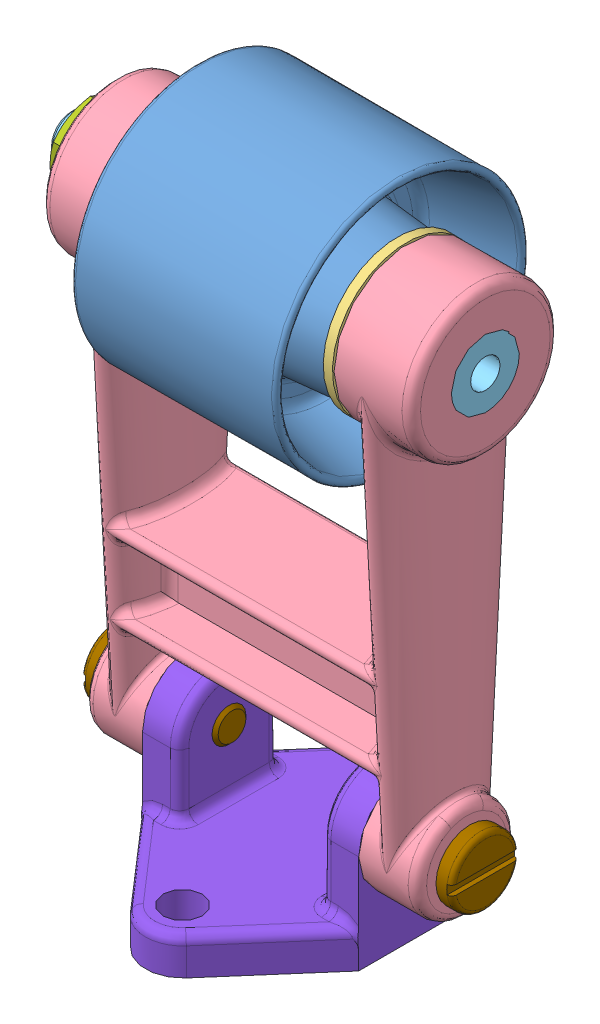
SolidWorks assembly ASSEMBLY v1, configuration Default. Lengths in mm.
Overall size (134.09 213.84 100).
11 component instances, 9 part files, 23 mates.
Components (placement in the parent):
- PULLEY v2-1: PULLEY v2 [Default] at origin size (68.15 83.68 83.68)
- BUSHING v2-1: BUSHING v2 [Default] at origin size (63 26.9 26.9)
- WASHER v1-1: WASHER v1 [Default] at (31.5 0 0) x (0 0.448797 -0.893634) z (-1 0 0) size (48 48 3)
- WASHER v1-2: WASHER v1 [Default] at (-34.5 0 0) x (0 0.448797 -0.893634) z (-1 0 0) size (48 48 3)
- Frame_final-1: Frame_final [Default] at (0 -140 0) size (120 180 51.83)
- SHAFT-1: SHAFT [Default] at (-7 0 0) size (134 22 22)
- WOODRUFF KEY #406-1: WOODRUFF KEY #406 [Default] at (-46 11.1125 0) size (18.79 7.95 3.17)
- HEX NUT V1-2: HEX NUT V1 [Default] at (-69 0 0) x (-1 0 0) z (0 0 1) size (9 27.71 24)
- BRACKET-1: BRACKET [Default] at (0 -172 0) x (0 0 -1) z (1 0 0) size (100 48 70.6)
- PIN v2-1: PIN v2 [Default] at (-60 -140 0) size (38.09 22 22)
- PIN v2-2: PIN v2 [Default] at (60 -140 0) x (-1 0 0) z (0 0 -1) size (38.09 22 22)
Mates (geometry in assembly coordinates):
- Concentric1: concentric aligned: cylinder of PULLEY v2-1 through (-113.6273 0 0) axis (-1 0 0) radius 13.45; cylinder of BUSHING v2-1 through (-66.3727 0 0) axis (-1 0 0) radius 13.45
- Coincident1: coincident aligned: plane of PULLEY v2-1 through (31.5 22 0) normal (1 0 0); plane of BUSHING v2-1 through (31.5 13.45 0) normal (1 0 0)
- Coincident2: coincident aligned: plane of BUSHING v2-1 through (0 0 0) normal (0 0 1); plane of assembly through (0 0 0) normal (0 0 1)
- Concentric4: concentric aligned: cylinder of BUSHING v2-1 through (-66.3727 0 0) axis (-1 0 0) radius 9.6216; cylinder of WASHER v1-1 through (34.501 0 0) axis (-1 0 0) radius 9.5
- Coincident4: coincident anti-aligned: plane of BUSHING v2-1 through (31.5 13.45 0) normal (1 0 0); plane of WASHER v1-1 through (31.5 0 0) normal (-1 0 0)
- Concentric5: concentric anti-aligned: cylinder of BUSHING v2-1 through (-66.3727 0 0) axis (-1 0 0) radius 9.6216; cylinder of Frame_final-1 through (-60.001 0 0) axis (1 0 0) radius 11
- Distance1: distance = 35 mm aligned: plane of Frame_final-1 through (-35 0 0) normal (1 0 0); plane of assembly through (0 0 0) normal (1 0 0)
- Coincident6: coincident aligned: plane of Frame_final-1 through (0 -140 0) normal (0 0 1); plane of assembly through (0 0 0) normal (0 0 1)
- Concentric6: concentric anti-aligned: cylinder of SHAFT-1 through (-46 11.1125 -1.5875) axis (0 0 1) radius 9.525; cylinder of WOODRUFF KEY #406-1 through (-46 11.1125 1.5875) axis (0 0 -1) radius 9.525
- Coincident7: coincident aligned: plane of SHAFT-1 through (-7 0 0) normal (0 0 1); plane of WOODRUFF KEY #406-1 through (-46 11.1125 0) normal (0 0 1)
- Concentric7: concentric anti-aligned: cylinder of Frame_final-1 through (-60.001 0 0) axis (1 0 0) radius 11; cylinder of SHAFT-1 through (-91.9355 0 0) axis (-1 0 0) radius 11
- Coincident8: coincident aligned: plane of Frame_final-1 through (60 0 0) normal (1 0 0); plane of SHAFT-1 through (60 0 0) normal (1 0 0)
- Parallel2: parallel aligned: plane of SHAFT-1 through (-7 0 0) normal (0 1 0); plane of WOODRUFF KEY #406-1 through (-46 11.1125 0) normal (0 1 0)
- Coincident10: coincident aligned: plane of SHAFT-1 through (-7 0 0) normal (0 0 1); plane of assembly through (0 0 0) normal (0 0 1)
- Concentric8: concentric aligned: cylinder of Frame_final-1 through (60.001 0 0) axis (-1 0 0) radius 8; cylinder of HEX NUT V1-2 through (-69 0 0) axis (-1 0 0) radius 7
- Coincident11: coincident anti-aligned: plane of Frame_final-1 through (-60 0 0) normal (-1 0 0); plane of HEX NUT V1-2 through (-60 0 0) normal (1 0 0)
- Coincident14: coincident aligned: plane of HEX NUT V1-2 through (-69 0 0) normal (0 0 1); plane of assembly through (0 0 0) normal (0 0 1)
- Concentric9: concentric anti-aligned: cylinder of Frame_final-1 through (54 -140 0) axis (-1 0 0) radius 8; cylinder of BRACKET-1 through (35 -140 0) axis (1 0 0) radius 5.1
- Coincident15: coincident anti-aligned: plane of Frame_final-1 through (35 -140 0) normal (-1 0 0); plane of BRACKET-1 through (35 -160 16) normal (1 0 0)
- Coincident17: coincident anti-aligned: plane of BRACKET-1 through (0 -172 0) normal (0 0 -1); plane of assembly through (0 0 0) normal (0 0 1)
- Concentric10: concentric aligned: cylinder of BRACKET-1 through (-35 -140 0) axis (-1 0 0) radius 5.1; cylinder of PIN v2-1 through (-157.3189 -140 0) axis (-1 0 0) radius 6
- Coincident18: coincident anti-aligned: plane of BRACKET-1 through (-35 -160 16) normal (-1 0 0); plane of PIN v2-1 through (-35 -132 0) normal (1 0 0)
- Perpendicular1: perpendicular: plane of PIN v2-1 through (-60 -140 0) normal (0 1 0); plane of assembly through (0 0 0) normal (0 0 1)
